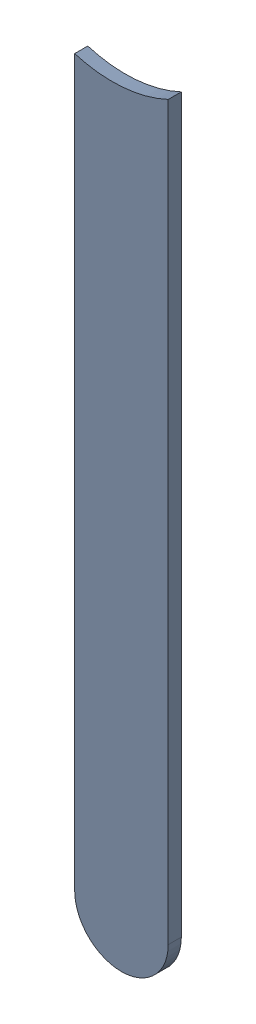
SolidWorks assembly Track (26.225mm,8.691mm)(26.225mm,10.975mm) on Top Layer, configuration Predeterminado. Lengths in mm.
Overall size (0.25 2.11 0.04).
2 component instances, 1 part files, 0 mates.
Components (placement in the parent):
- Track (26.225mm,8.691mm)(26.225mm,10.975mm) on Top Layer-1-1: Track (26.225mm,8.691mm)(26.225mm,10.975mm) on Top Layer-1 [Predeterminado] at (-68.317 -44.187 -0.0457) size (0.25 2.11 0.04)
  - Track (26.225mm,8.691mm)(26.225mm,10.975mm) on Top Layer-Part-1-1: Track (26.225mm,8.691mm)(26.225mm,10.975mm) on Top Layer-Part-1 [Predeterminado] at origin size (0.25 2.11 0.04)
